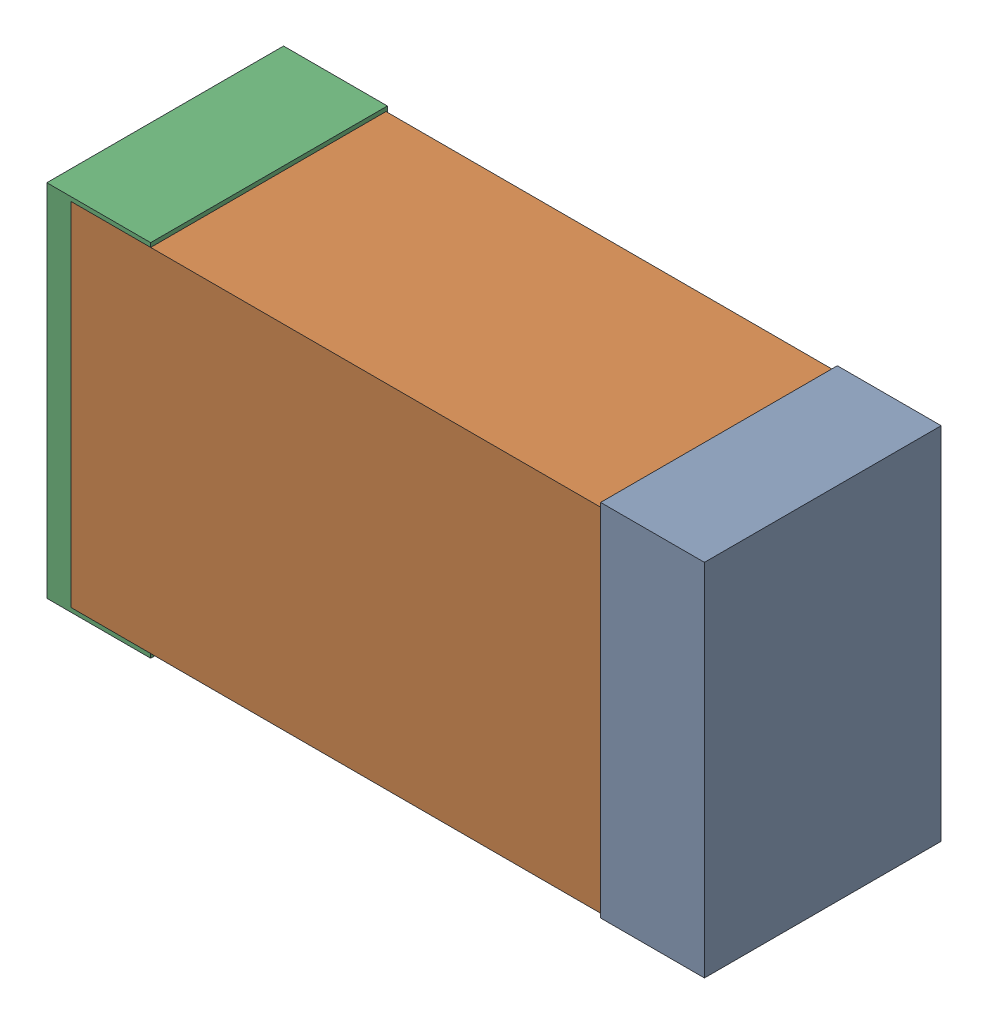
SolidWorks assembly USB45_FB3, configuration Default. Lengths in mm.
Overall size (2.38 1.3 0.85).
6 component instances, 2 part files, 0 mates.
Components (placement in the parent):
- 384311232-1: 384311232 [Default] at (163.814 36.449 -1.9574) size (0.38 1.3 0.85)
  - Extruded_8-1: Extruded_8 [Default] at origin size (0.38 1.3 0.85)
- 384311360-1: 384311360 [Default] at (162.814 36.449 -1.9524) size (2.2 1.27 0.85)
  - Extruded_9-1: Extruded_9 [Default] at origin size (2.2 1.27 0.85)
- 384311232-2: 384311232 [Default] at (161.814 36.449 -1.9574) size (0.38 1.3 0.85)
  - Extruded_8-1: Extruded_8 [Default] at origin size (0.38 1.3 0.85)
